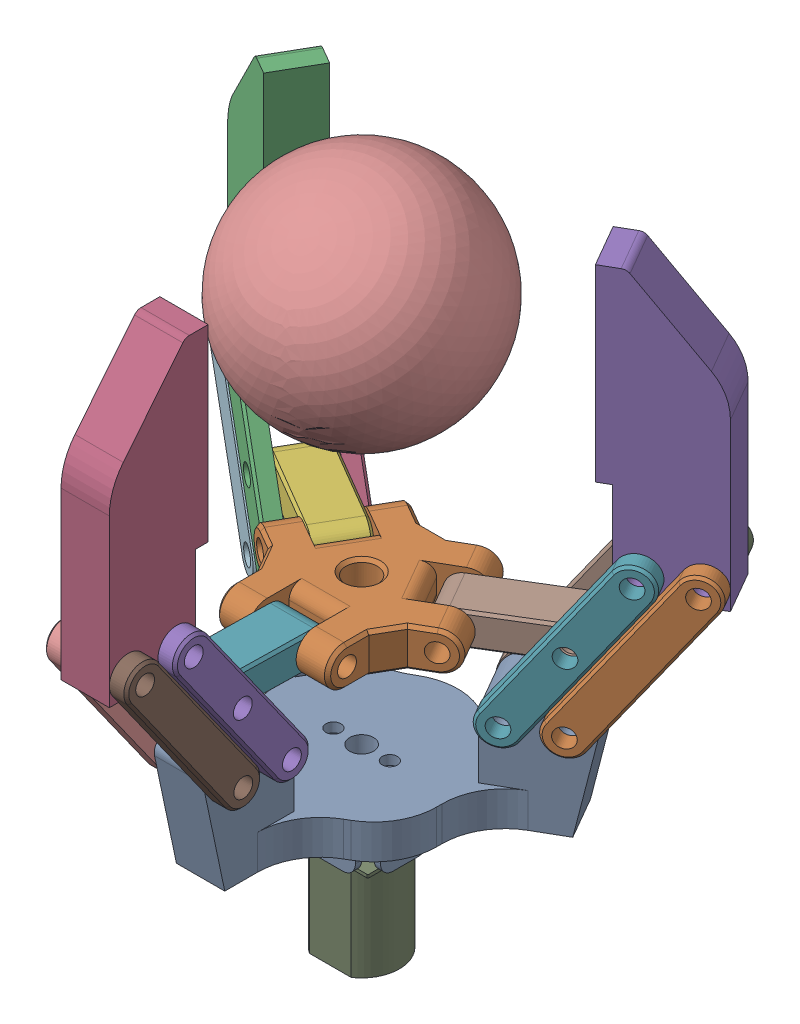
SolidWorks assembly total, configuration Default. Lengths in mm.
Overall size (84.9 118.79 74.75).
22 component instances, 8 part files, 68 mates.
Components (placement in the parent):
- Base_part-1: Base_part [Default] at (-1.3918 -7.201 17.9318) size (54.42 26.5 47.13)
- Elevetor_part-1: Elevetor_part [Default] at (-1.3918 19.039 17.9318) size (33.09 6.2 28.84)
- Connecting_rod_3_part-1: Connecting_rod_3_part [Default] at (-26.0582 19.3033 9.695) x (0.501665 -0.815134 0.289636) z (-0.705927 -0.579273 -0.407567) size (33 2.7 6)
- Connecting_rod_3_part-2: Connecting_rod_3_part [Default] at (-20.8582 19.3033 0.6883) x (0.501665 -0.815134 0.289636) z (0.705927 0.579273 0.407567) size (33 2.7 6)
- Connecting_rod_3_part-3: Connecting_rod_3_part [Default] at (3.8082 19.3033 43.4119) x (0 -0.815134 -0.579273) z (0 -0.579273 0.815134) size (33 2.7 6)
- Connecting_rod_3_part-4: Connecting_rod_3_part [Default] at (-6.5918 19.3033 43.4119) x (0 0.815134 0.579273) z (0 -0.579273 0.815134) size (33 2.7 6)
- Connecting_rod_3_part-5: Connecting_rod_3_part [Default] at (23.2747 19.3033 9.695) x (0.501665 0.815134 -0.289636) z (0.705927 -0.579273 -0.407567) size (33 2.7 6)
- Connecting_rod_3_part-6: Connecting_rod_3_part [Default] at (18.0747 19.3033 0.6883) x (0.501665 0.815134 -0.289636) z (-0.705927 0.579273 0.407567) size (33 2.7 6)
- Connecting_rod_2_part-1: Connecting_rod_2_part [Default] at (24.7864 19.3033 -3.1867) x (0.501665 0.815134 -0.289636) z (-0.705927 0.579273 0.407567) size (33 2.7 6)
- Connecting_rod_2_part-2: Connecting_rod_2_part [Default] at (-6.5918 19.3033 51.1619) x (0 0.815134 0.579273) z (0 -0.579273 0.815134) size (33 2.7 6)
- Connecting_rod_2_part-3: Connecting_rod_2_part [Default] at (3.8082 19.3033 51.1619) x (0 -0.815134 -0.579273) z (0 -0.579273 0.815134) size (33 2.7 6)
- Connecting_rod_2_part-4: Connecting_rod_2_part [Default] at (-32.7699 19.3033 5.82) x (0.501665 -0.815134 0.289636) z (-0.705927 -0.579273 -0.407567) size (33 2.7 6)
- Connecting_rod_2_part-5: Connecting_rod_2_part [Default] at (-27.5699 19.3033 -3.1867) x (0.501665 -0.815134 0.289636) z (0.705927 0.579273 0.407567) size (33 2.7 6)
- Connecting_rod_2_part-6: Connecting_rod_2_part [Default] at (29.9864 19.3033 5.82) x (0.501665 0.815134 -0.289636) z (0.705927 -0.579273 -0.407567) size (33 2.7 6)
- Gripper1_part-1: Gripper1_part [Default] at (-27.6327 42.3076 2.7816) x (0.866025 0 0.5) z (0 -1 0) size (15.75 7.7 45)
- Gripper1_part-3: Gripper1_part [Default] at (-1.3918 42.3076 48.2321) x (0 0 -1) z (0 -1 0) size (15.75 7.7 45)
- Gripper1_part-4: Gripper1_part [Default] at (24.8491 42.3076 2.7816) x (-0.866025 0 0.5) z (0 -1 0) size (15.75 7.7 45)
- Connecting_rod_1_part-1: Connecting_rod_1_part [Default] at (-18.2945 19.1931 8.173) x (0.865877 -0.018483 0.499915) z (0.016007 0.999829 0.009241) size (19.5 7.7 5.2)
- Connecting_rod_1_part-2: Connecting_rod_1_part [Default] at (-1.3918 19.1931 37.4493) x (0 -0.018483 -0.999829) z (0 -0.999829 0.018483) size (19.5 7.7 5.2)
- Connecting_rod_1_part-3: Connecting_rod_1_part [Default] at (13.4564 19.1492 9.3591) x (0.865877 0.018483 -0.499915) z (-0.016007 0.999829 0.009241) size (19.5 7.7 5.2)
- DC_motor_part-1: DC_motor_part [Default] at (-1.3918 -29.701 17.9318) x (1 0 0) z (0 0 -1) size (12 26 10)
- ball-1: ball [Default] at (-1.3918 60.4034 17.9318) x (0.949383 0.115758 -0.292013) z (0.299666 -0.612509 0.731459) size (36 36 36)
Mates (geometry in assembly coordinates):
- Concentrico1: concentric anti-aligned: cylinder of Base_part-1 through (-1.3918 -7.201 17.9318) axis (0 1 0) radius 1.9; cylinder of Elevetor_part-1 through (-1.3918 22.139 17.9318) axis (0 -1 0) radius 2.5
- Coincidente1: coincident anti-aligned: plane of Base_part-1 through (13.2292 -1.701 13.9359) normal (0.5 0 0.866025); plane of Elevetor_part-1 through (13.2271 22.139 13.9371) normal (-0.5 0 -0.866025)
- Coincidente2: coincident anti-aligned: plane of Base_part-1 through (22.3696 -1.701 -0.2324) normal (-0.5 0 -0.866025); plane of Elevetor_part-1 through (9.3771 22.139 7.2687) normal (0.5 0 0.866025)
- Coincidente3: coincident anti-aligned: plane of Base_part-1 through (-12.1627 -1.701 7.2676) normal (0.5 0 -0.866025); plane of Elevetor_part-1 through (-12.1606 22.139 7.2687) normal (-0.5 0 0.866025)
- Coincidente4: coincident anti-aligned: plane of Base_part-1 through (-29.0031 -1.701 6.4359) normal (-0.5 0 0.866025); plane of Elevetor_part-1 through (-16.0106 22.139 13.9371) normal (0.5 0 -0.866025)
- Coincidente5: coincident anti-aligned: plane of Base_part-1 through (2.4582 -1.701 47.5918) normal (1 0 0); plane of Elevetor_part-1 through (2.4582 22.139 32.5894) normal (-1 0 0)
- Coincidente6: coincident anti-aligned: plane of Base_part-1 through (-5.2418 -1.701 32.5918) normal (-1 0 0); plane of Elevetor_part-1 through (-5.2418 22.139 32.5894) normal (1 0 0)
- Coincidente7: coincident anti-aligned: plane of Base_part-1 through (-29.0031 -1.701 6.4359) normal (-0.5 0 0.866025); plane of Connecting_rod_3_part-1 through (-32.1557 30.3076 4.6158) normal (0.5 0 -0.866025)
- Concentrico2: concentric aligned: cylinder of Base_part-1 through (-18.6108 8.299 12.4359) axis (0.5 0 -0.866025) radius 1.5; cylinder of Connecting_rod_3_part-1 through (-19.9608 8.299 14.7742) axis (0.5 0 -0.866025) radius 1.5
- Coincidente8: coincident anti-aligned: plane of Base_part-1 through (-12.1627 -1.701 7.2676) normal (0.5 0 -0.866025); plane of Connecting_rod_3_part-2 through (-28.3057 30.3076 -2.0526) normal (-0.5 0 0.866025)
- Concentrico3: concentric anti-aligned: cylinder of Base_part-1 through (-18.6108 8.299 12.4359) axis (0.5 0 -0.866025) radius 1.5; cylinder of Connecting_rod_3_part-2 through (-13.4108 8.299 3.4293) axis (-0.5 0 0.866025) radius 1.5
- Coincidente9: coincident anti-aligned: plane of Base_part-1 through (22.3696 -1.701 -0.2324) normal (-0.5 0 -0.866025); plane of Connecting_rod_3_part-6 through (11.9772 8.299 5.7676) normal (0.5 0 0.866025)
- Concentrico4: concentric aligned: cylinder of Base_part-1 through (11.9772 8.299 5.7676) axis (0.5 0 0.866025) radius 1.5; cylinder of Connecting_rod_3_part-6 through (10.6272 8.299 3.4293) axis (0.5 0 0.866025) radius 1.5
- Coincidente10: coincident anti-aligned: plane of Base_part-1 through (13.2292 -1.701 13.9359) normal (0.5 0 0.866025); plane of Connecting_rod_3_part-5 through (15.8272 8.299 12.4359) normal (-0.5 0 -0.866025)
- Concentrico5: concentric anti-aligned: cylinder of Base_part-1 through (11.9772 8.299 5.7676) axis (0.5 0 0.866025) radius 1.5; cylinder of Connecting_rod_3_part-5 through (17.1772 8.299 14.7742) axis (-0.5 0 -0.866025) radius 1.5
- Coincidente11: coincident anti-aligned: plane of Base_part-1 through (2.4582 -1.701 47.5918) normal (1 0 0); plane of Connecting_rod_3_part-3 through (2.4582 30.3076 51.2321) normal (-1 0 0)
- Concentrico6: concentric aligned: cylinder of Base_part-1 through (2.4582 8.299 35.5918) axis (-1 0 0) radius 1.5; cylinder of Connecting_rod_3_part-3 through (5.1582 8.299 35.5918) axis (-1 0 0) radius 1.5
- Coincidente12: coincident anti-aligned: plane of Base_part-1 through (-5.2418 -1.701 32.5918) normal (-1 0 0); plane of Connecting_rod_3_part-4 through (-5.2418 8.299 35.5918) normal (1 0 0)
- Concentrico7: concentric anti-aligned: cylinder of Base_part-1 through (2.4582 8.299 35.5918) axis (-1 0 0) radius 1.5; cylinder of Connecting_rod_3_part-4 through (-7.9418 8.299 35.5918) axis (1 0 0) radius 1.5
- Coincidente13: coincident anti-aligned: plane of Base_part-1 through (-29.0031 -1.701 6.4359) normal (-0.5 0 0.866025); plane of Connecting_rod_2_part-4 through (-38.8674 30.3076 0.7408) normal (0.5 0 -0.866025)
- Concentrico8: concentric aligned: cylinder of Base_part-1 through (-25.3225 8.299 8.5609) axis (0.5 0 -0.866025) radius 1.5; cylinder of Connecting_rod_2_part-4 through (-26.6725 8.299 10.8992) axis (0.5 0 -0.866025) radius 1.5
- Coincidente14: coincident anti-aligned: plane of Base_part-1 through (-12.1627 -1.701 7.2676) normal (0.5 0 -0.866025); plane of Connecting_rod_2_part-5 through (-35.0174 30.3076 -5.9276) normal (-0.5 0 0.866025)
- Concentrico9: concentric anti-aligned: cylinder of Base_part-1 through (-25.3225 8.299 8.5609) axis (0.5 0 -0.866025) radius 1.5; cylinder of Connecting_rod_2_part-5 through (-20.1225 8.299 -0.4457) axis (-0.5 0 0.866025) radius 1.5
- Coincidente15: coincident anti-aligned: plane of Base_part-1 through (22.3696 -1.701 -0.2324) normal (-0.5 0 -0.866025); plane of Connecting_rod_2_part-1 through (18.6889 8.299 1.8926) normal (0.5 0 0.866025)
- Concentrico10: concentric aligned: cylinder of Base_part-1 through (18.6889 8.299 1.8926) axis (0.5 0 0.866025) radius 1.5; cylinder of Connecting_rod_2_part-1 through (17.3389 8.299 -0.4457) axis (0.5 0 0.866025) radius 1.5
- Coincidente16: coincident anti-aligned: plane of Base_part-1 through (13.2292 -1.701 13.9359) normal (0.5 0 0.866025); plane of Connecting_rod_2_part-6 through (22.5389 8.299 8.5609) normal (-0.5 0 -0.866025)
- Concentrico11: concentric anti-aligned: cylinder of Base_part-1 through (18.6889 8.299 1.8926) axis (0.5 0 0.866025) radius 1.5; cylinder of Connecting_rod_2_part-6 through (23.8889 8.299 10.8992) axis (-0.5 0 -0.866025) radius 1.5
- Coincidente17: coincident anti-aligned: plane of Base_part-1 through (2.4582 -1.701 47.5918) normal (1 0 0); plane of Connecting_rod_2_part-3 through (2.4582 30.3076 58.9821) normal (-1 0 0)
- Concentrico12: concentric aligned: cylinder of Base_part-1 through (2.4582 8.299 43.3418) axis (-1 0 0) radius 1.5; cylinder of Connecting_rod_2_part-3 through (5.1582 8.299 43.3418) axis (-1 0 0) radius 1.5
- Coincidente18: coincident anti-aligned: plane of Base_part-1 through (-5.2418 -1.701 32.5918) normal (-1 0 0); plane of Connecting_rod_2_part-2 through (-5.2418 8.299 43.3418) normal (1 0 0)
- Concentrico13: concentric anti-aligned: cylinder of Base_part-1 through (2.4582 8.299 43.3418) axis (-1 0 0) radius 1.5; cylinder of Connecting_rod_2_part-2 through (-7.9418 8.299 43.3418) axis (1 0 0) radius 1.5
- Coincidente19: coincident anti-aligned: plane of Connecting_rod_2_part-4 through (-38.8674 30.3076 0.7408) normal (0.5 0 -0.866025); plane of Gripper1_part-1 through (-29.5577 42.3076 6.1158) normal (-0.5 0 0.866025)
- Coincidente20: coincident anti-aligned: plane of Connecting_rod_3_part-1 through (-32.1557 30.3076 4.6158) normal (0.5 0 -0.866025); plane of Gripper1_part-1 through (-29.5577 42.3076 6.1158) normal (-0.5 0 0.866025)
- Coincidente21: coincident anti-aligned: plane of Connecting_rod_2_part-5 through (-35.0174 30.3076 -5.9276) normal (-0.5 0 0.866025); plane of Gripper1_part-1 through (-25.7077 42.3076 -0.5526) normal (0.5 0 -0.866025)
- Concentrico14: concentric aligned: cylinder of Connecting_rod_3_part-1 through (-33.5057 30.3076 6.954) axis (0.5 0 -0.866025) radius 1.5; cylinder of Gripper1_part-1 through (-32.1557 30.3076 4.6158) axis (0.5 0 -0.866025) radius 1.5
- Concentrico15: concentric anti-aligned: cylinder of Connecting_rod_3_part-2 through (-26.9557 30.3076 -4.3909) axis (-0.5 0 0.866025) radius 1.5; cylinder of Gripper1_part-1 through (-32.1557 30.3076 4.6158) axis (0.5 0 -0.866025) radius 1.5
- Concentrico16: concentric anti-aligned: cylinder of Connecting_rod_2_part-5 through (-33.6674 30.3076 -8.2659) axis (-0.5 0 0.866025) radius 1.5; cylinder of Gripper1_part-1 through (-38.8674 30.3076 0.7408) axis (0.5 0 -0.866025) radius 1.5
- Concentrico17: concentric aligned: cylinder of Connecting_rod_2_part-4 through (-40.2174 30.3076 3.079) axis (0.5 0 -0.866025) radius 1.5; cylinder of Gripper1_part-1 through (-38.8674 30.3076 0.7408) axis (0.5 0 -0.866025) radius 1.5
- Coincidente22: coincident anti-aligned: plane of Connecting_rod_2_part-1 through (18.6889 8.299 1.8926) normal (0.5 0 0.866025); plane of Gripper1_part-4 through (22.9241 42.3076 -0.5526) normal (-0.5 0 -0.866025)
- Concentrico18: concentric aligned: cylinder of Connecting_rod_3_part-6 through (24.1722 30.3076 -4.3909) axis (0.5 0 0.866025) radius 1.5; cylinder of Gripper1_part-4 through (25.5222 30.3076 -2.0526) axis (0.5 0 0.866025) radius 1.5
- Concentrico19: concentric anti-aligned: cylinder of Connecting_rod_3_part-5 through (30.7222 30.3076 6.954) axis (-0.5 0 -0.866025) radius 1.5; cylinder of Gripper1_part-4 through (25.5222 30.3076 -2.0526) axis (0.5 0 0.866025) radius 1.5
- Concentrico20: concentric anti-aligned: cylinder of Connecting_rod_2_part-6 through (37.4339 30.3076 3.079) axis (-0.5 0 -0.866025) radius 1.5; cylinder of Gripper1_part-4 through (32.2339 30.3076 -5.9276) axis (0.5 0 0.866025) radius 1.5
- Concentrico21: concentric aligned: cylinder of Connecting_rod_2_part-1 through (30.8839 30.3076 -8.2659) axis (0.5 0 0.866025) radius 1.5; cylinder of Gripper1_part-4 through (32.2339 30.3076 -5.9276) axis (0.5 0 0.866025) radius 1.5
- Coincidente23: coincident anti-aligned: plane of Connecting_rod_2_part-2 through (-5.2418 8.299 43.3418) normal (1 0 0); plane of Gripper1_part-3 through (-5.2418 42.3076 48.2321) normal (-1 0 0)
- Concentrico22: concentric aligned: cylinder of Connecting_rod_3_part-3 through (5.1582 30.3076 51.2321) axis (-1 0 0) radius 1.5; cylinder of Gripper1_part-3 through (2.4582 30.3076 51.2321) axis (-1 0 0) radius 1.5
- Concentrico23: concentric aligned: cylinder of Connecting_rod_2_part-3 through (5.1582 30.3076 58.9821) axis (-1 0 0) radius 1.5; cylinder of Gripper1_part-3 through (2.4582 30.3076 58.9821) axis (-1 0 0) radius 1.5
- Concentrico24: concentric anti-aligned: cylinder of Connecting_rod_3_part-4 through (-7.9418 30.3076 51.2321) axis (1 0 0) radius 1.5; cylinder of Gripper1_part-3 through (2.4582 30.3076 51.2321) axis (-1 0 0) radius 1.5
- Concentrico25: concentric anti-aligned: cylinder of Connecting_rod_2_part-2 through (-7.9418 30.3076 58.9821) axis (1 0 0) radius 1.5; cylinder of Gripper1_part-3 through (2.4582 30.3076 58.9821) axis (-1 0 0) radius 1.5
- Coincidente24: coincident anti-aligned: plane of Elevetor_part-1 through (9.3771 22.139 7.2687) normal (0.5 0 0.866025); plane of Connecting_rod_1_part-3 through (6.3677 19.039 9.0062) normal (-0.5 0 -0.866025)
- Concentrico26: concentric aligned: cylinder of Elevetor_part-1 through (-2.4793 19.039 -6.3171) axis (0.5 0 0.866025) radius 1.5; cylinder of Connecting_rod_1_part-3 through (6.3677 19.039 9.0062) axis (0.5 0 0.866025) radius 1.5
- Coincidente25: coincident anti-aligned: plane of Connecting_rod_3_part-5 through (15.8272 8.299 12.4359) normal (-0.5 0 -0.866025); plane of Connecting_rod_1_part-3 through (10.2177 19.039 15.6746) normal (0.5 0 0.866025)
- Concentrico27: concentric anti-aligned: cylinder of Connecting_rod_3_part-5 through (23.9497 19.3033 10.8641) axis (-0.5 0 -0.866025) radius 1.5; cylinder of Connecting_rod_1_part-3 through (18.7497 19.3033 1.8575) axis (0.5 0 0.866025) radius 1.5
- Coincidente26: coincident anti-aligned: plane of Connecting_rod_3_part-2 through (-28.3057 30.3076 -2.0526) normal (-0.5 0 0.866025); plane of Connecting_rod_1_part-1 through (-21.5332 19.3033 1.8575) normal (0.5 0 -0.866025)
- Coincidente27: coincident anti-aligned: plane of Elevetor_part-1 through (-16.0106 22.139 13.9371) normal (0.5 0 -0.866025); plane of Connecting_rod_1_part-1 through (-25.3832 19.3033 8.5259) normal (-0.5 0 0.866025)
- Concentrico28: concentric anti-aligned: cylinder of Elevetor_part-1 through (-21.5405 19.039 30.4651) axis (0.5 0 -0.866025) radius 1.5; cylinder of Connecting_rod_1_part-1 through (-9.1512 19.039 9.0062) axis (-0.5 0 0.866025) radius 1.5
- Concentrico29: concentric anti-aligned: cylinder of Connecting_rod_3_part-1 through (-26.7332 19.3033 10.8641) axis (0.5 0 -0.866025) radius 1.5; cylinder of Connecting_rod_1_part-1 through (-21.5332 19.3033 1.8575) axis (-0.5 0 0.866025) radius 1.5
- Coincidente28: coincident anti-aligned: plane of Elevetor_part-1 through (2.4582 22.139 32.5894) normal (-1 0 0); plane of Connecting_rod_1_part-2 through (2.4582 19.3033 43.4119) normal (1 0 0)
- Coincidente29: coincident anti-aligned: plane of Elevetor_part-1 through (-5.2418 22.139 32.5894) normal (1 0 0); plane of Connecting_rod_1_part-2 through (-5.2418 19.3033 43.4119) normal (-1 0 0)
- Concentrico30: concentric aligned: cylinder of Elevetor_part-1 through (15.7271 19.039 29.1144) axis (-1 0 0) radius 1.5; cylinder of Connecting_rod_1_part-2 through (2.4582 19.039 29.1144) axis (-1 0 0) radius 1.5
- Concentrico33: concentric aligned: cylinder of Connecting_rod_3_part-3 through (5.1582 19.3033 43.4119) axis (-1 0 0) radius 1.5; cylinder of Connecting_rod_1_part-2 through (2.4582 19.3033 43.4119) axis (-1 0 0) radius 1.5
- Concentrico34: concentric aligned: cylinder of Base_part-1 through (-5.8918 0.499 17.9318) axis (0 -1 0) radius 0.5; cylinder of DC_motor_part-1 through (-5.8918 -5.701 17.9318) axis (0 -1 0) radius 0.5
- Concentrico35: concentric aligned: cylinder of Elevetor_part-1 through (-1.3918 22.139 17.9318) axis (0 -1 0) radius 2.5; cylinder of DC_motor_part-1 through (-1.3918 -5.701 17.9318) axis (0 -1 0) radius 1.5
- Concentrico36: concentric aligned: cylinder of Base_part-1 through (-5.8918 0.499 17.9318) axis (0 -1 0) radius 0.5; cylinder of DC_motor_part-1 through (-5.8918 -5.701 17.9318) axis (0 -1 0) radius 0.5
- Coincidente31: coincident anti-aligned: plane of Base_part-1 through (-1.3918 -5.701 17.9318) normal (0 -1 0); plane of DC_motor_part-1 through (-7.2402 -5.701 22.7802) normal (0 1 0)
- Parallel1: parallel anti-aligned: plane of Base_part-1 through (-1.3918 -1.701 17.9318) normal (0 1 0); plane of Gripper1_part-4 through (22.9241 27.3076 -0.5526) normal (0 -1 0)
- Parallel2: parallel anti-aligned: plane of Base_part-1 through (-1.3918 -1.701 17.9318) normal (0 1 0); plane of Gripper1_part-4 through (22.9241 27.3076 -0.5526) normal (0 -1 0)
- LimitDistance1: limit distance = 17.64 mm anti-aligned: plane of Elevetor_part-1 through (-1.3918 15.939 17.9318) normal (0 -1 0); plane of Base_part-1 through (-1.3918 -1.701 17.9318) normal (0 1 0)
- Concentrico37: concentric: cylinder of Base_part-1 through (-1.3918 -7.201 17.9318) axis (0 1 0) radius 1.9; sphere of ball-1
